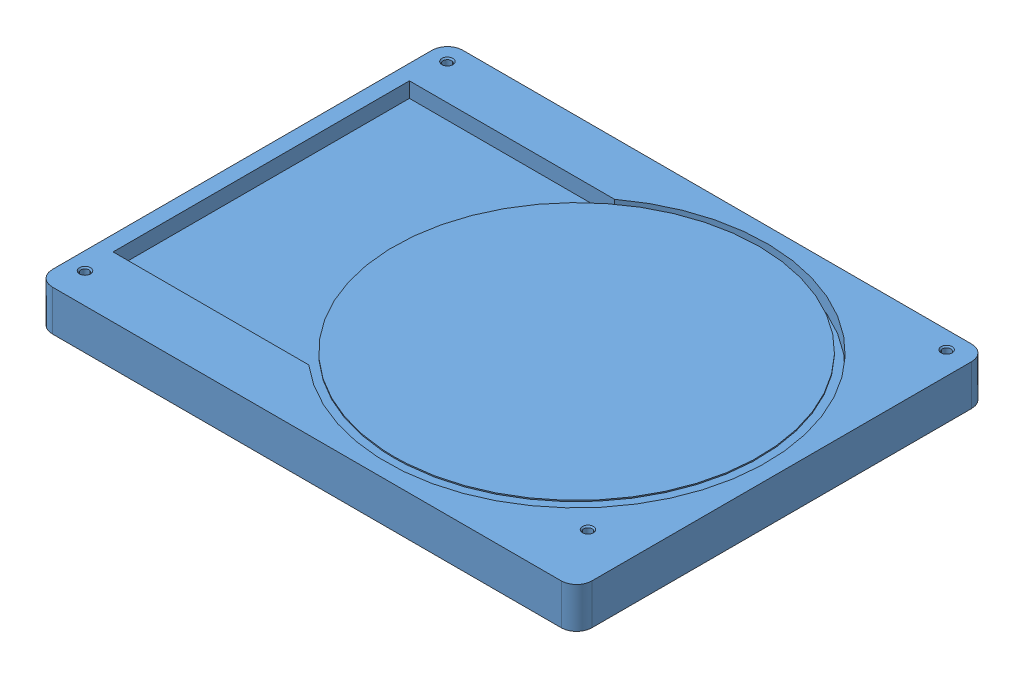
SolidWorks assembly Basic HDD model 1 platter, configuration Default. Lengths in mm.
Overall size (71 4.3 54).
2 component instances, 2 part files, 3 mates.
Components (placement in the parent):
- HDD Base 1 platter-1: HDD Base 1 platter [Default] at (32.3272 25.8165 59.0579) size (71 4.3 54)
- HDD Top 1 platter-1: HDD Top 1 platter [Default] at (32.3272 28.3165 59.0579) (suppressed, hidden)
Mates (geometry in assembly coordinates):
- Coincident1: coincident anti-aligned: plane of HDD Base 1 platter-1 through (32.3272 29.9665 59.0579) normal (0 1 0); plane of HDD Top 1 platter-1 through (32.3272 28.3165 59.0579) normal (0 -1 0)
- Concentric1: concentric aligned: cylinder of HDD Base 1 platter-1 through (61.7272 29.9665 78.4579) axis (0 1 0) radius 0.55; cylinder of HDD Top 1 platter-1 through (61.7272 30.8165 78.4579) axis (0 1 0) radius 0.55
- Concentric2: concentric aligned: cylinder of HDD Base 1 platter-1 through (-0.8728 29.9665 82.0579) axis (0 1 0) radius 0.55; cylinder of HDD Top 1 platter-1 through (-0.8728 30.8165 82.0579) axis (0 1 0) radius 0.55
